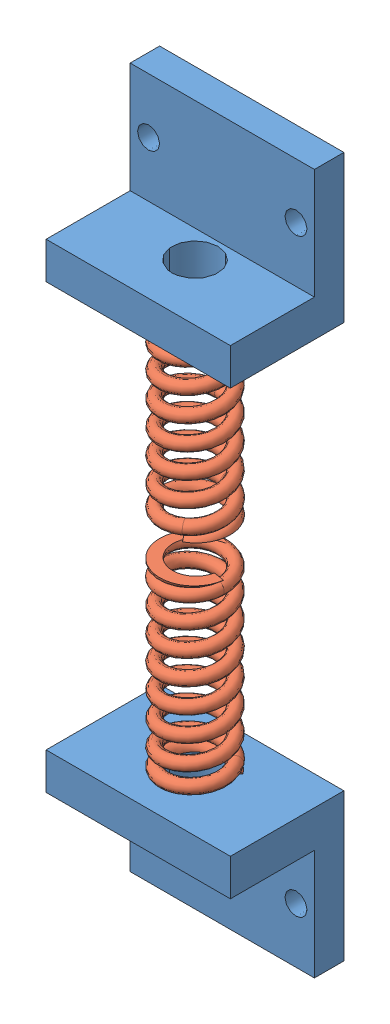
SolidWorks assembly spring-pack, configuration Default. Lengths in mm.
Overall size (31.75 120.65 19.56).
4 component instances, 2 part files, 6 mates.
Components (placement in the parent):
- y09-spring-holder-1: y09-spring-holder [Default] at origin size (31.75 25.4 19.56)
- Lee2E9-1: Lee2E9 [Default] at (0 46.1032 0) x (0.4998 0 0.866141) z (0 1 0) size (13.87 13.94 34.98)
- Lee2E9-2: Lee2E9 [Default] at (0 36.4468 0) x (0.987904 0 0.155065) z (0 -1 0) size (13.87 13.94 34.98)
- y09-spring-holder-2: y09-spring-holder [Default] at (0 82.55 0) x (-1 0 0) z (0 0 1) size (31.75 25.4 19.56)
Mates (geometry in assembly coordinates):
- Concentric1: concentric anti-aligned: cylinder of y09-spring-holder-1; line of Lee2E9-2
- Coincident2: coincident anti-aligned: line of Lee2E9-1; line of y09-spring-holder-2
- Coincident3: coincident aligned: plane of y09-spring-holder-1 through (-15.875 6.35 9.779) normal (0 0 1); plane of y09-spring-holder-2 through (15.875 76.2 9.779) normal (0 0 1)
- Distance1: distance = 69.85 mm anti-aligned: plane of y09-spring-holder-1 through (-15.875 6.35 9.779) normal (0 1 0); plane of y09-spring-holder-2 through (15.875 76.2 9.779) normal (0 -1 0)
- Coincident4: coincident anti-aligned: plane of Lee2E9-1; plane of y09-spring-holder-2 through (15.875 76.2 9.779) normal (0 -1 0)
- Coincident5: coincident anti-aligned: plane of y09-spring-holder-1 through (-15.875 6.35 9.779) normal (0 1 0); plane of Lee2E9-2
